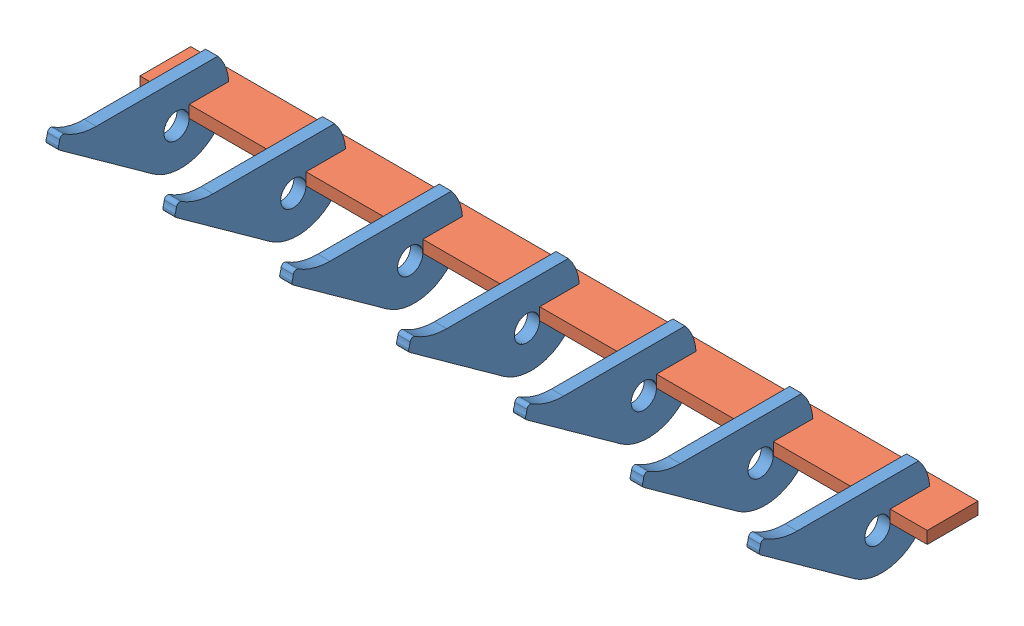
SolidWorks assembly Diverter Mechanism, configuration Default. Lengths in mm.
Overall size (196.85 43.8 48.01).
8 component instances, 2 part files, 3 mates.
Components (placement in the parent):
- Diverter Tab-1: Diverter Tab [Default] at (0 0.127 -1.4566) x (1 0 0) z (0 -0.811308 0.58462) size (3.05 42.17 23.6)
- Diverter Tab-2: Diverter Tab [Default] at (-29.21 0.127 -1.4566) x (1 0 0) z (0 -0.811308 0.58462) size (3.05 42.17 23.6)
- Diverter Tab-3: Diverter Tab [Default] at (-58.42 0.127 -1.4566) x (1 0 0) z (0 -0.811308 0.58462) size (3.05 42.17 23.6)
- Diverter Tab-4: Diverter Tab [Default] at (-87.63 0.127 -1.4566) x (1 0 0) z (0 -0.811308 0.58462) size (3.05 42.17 23.6)
- Diverter Tab-5: Diverter Tab [Default] at (29.21 0.127 -1.4566) x (1 0 0) z (0 -0.811308 0.58462) size (3.05 42.17 23.6)
- Diverter Tab-6: Diverter Tab [Default] at (58.42 0.127 -1.4566) x (1 0 0) z (0 -0.811308 0.58462) size (3.05 42.17 23.6)
- Diverter Tab-7: Diverter Tab [Default] at (87.63 0.127 -1.4566) x (1 0 0) z (0 -0.811308 0.58462) size (3.05 42.17 23.6)
- DiverterTabSpine-1: DiverterTabSpine [Default] at (0 0.127 -4.6316) size (196.85 3.05 12.7)
Mates (geometry in assembly coordinates):
- Coincident1: coincident aligned: plane of DiverterTabSpine-1 through (0 0.127 -4.6316) normal (1 0 0); plane of assembly through (0 0 0) normal (1 0 0)
- Coincident2: coincident anti-aligned: plane of Diverter Tab-7 through (86.106 3.175 -8.1728) normal (0 -1 0); plane of DiverterTabSpine-1 through (0 3.175 -4.6316) normal (0 1 0)
- Coincident3: coincident: cylinder of Diverter Tab-7 through (86.106 0.127 -1.4566) axis (1 0 0) radius 3.175; line of DiverterTabSpine-1 through (-98.425 0.127 -4.6316) axis (1 0 0)
